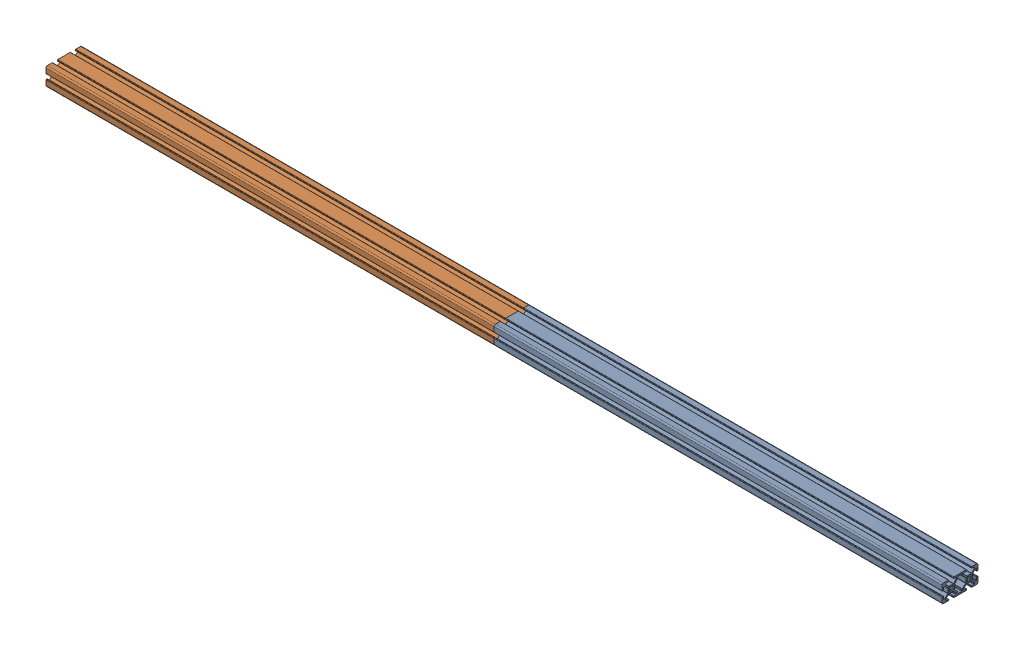
SolidWorks assembly BeltyV2-doubleSubAssem, configuration Default. Lengths in mm.
Overall size (1000 20 40).
2 component instances, 1 part files, 2 mates.
Components (placement in the parent):
- 2040-50-1: 2040-50 [Default] at (246.4668 -0.8099 2.4146) size (500 20 40)
- 2040-50-2: 2040-50 [Default] at (-253.5332 -0.8099 2.4146) size (500 20 40)
Mates (geometry in assembly coordinates):
- Coincident1: coincident: line of 2040-50-1 through (-253.5332 9.1901 20.9146) axis (0 0 -1); line of 2040-50-2 through (-253.5332 9.1901 20.9146) axis (0 0 -1)
- Coincident2: coincident aligned: line of 2040-50-1 through (-253.5332 2.3281 22.4146) axis (0 1 0); line of 2040-50-2 through (-253.5332 2.3281 22.4146) axis (0 1 0)
